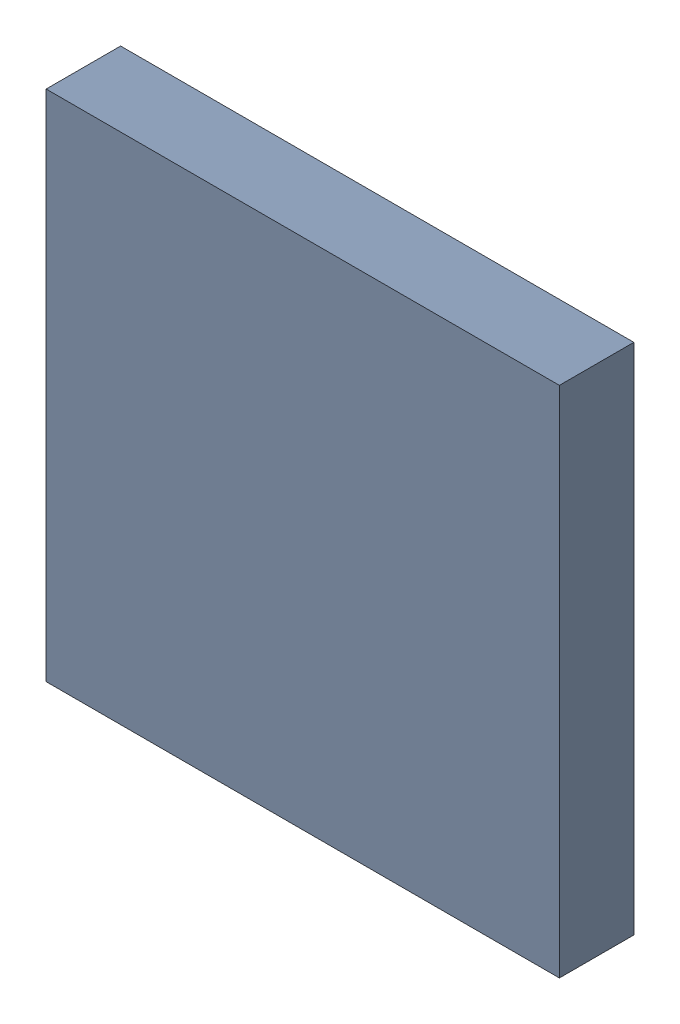
SolidWorks assembly 6327396160, configuration Default. Lengths in mm.
Overall size (1.75 1.75 0.25).
2 component instances, 1 part files, 0 mates.
Components (placement in the parent):
- 6701982208-1:  [Default] at (27.7 14.8 0) (suppressed, hidden)
- Extruded-21-1: Extruded-21 [Default] at origin size (1.75 1.75 0.25)
